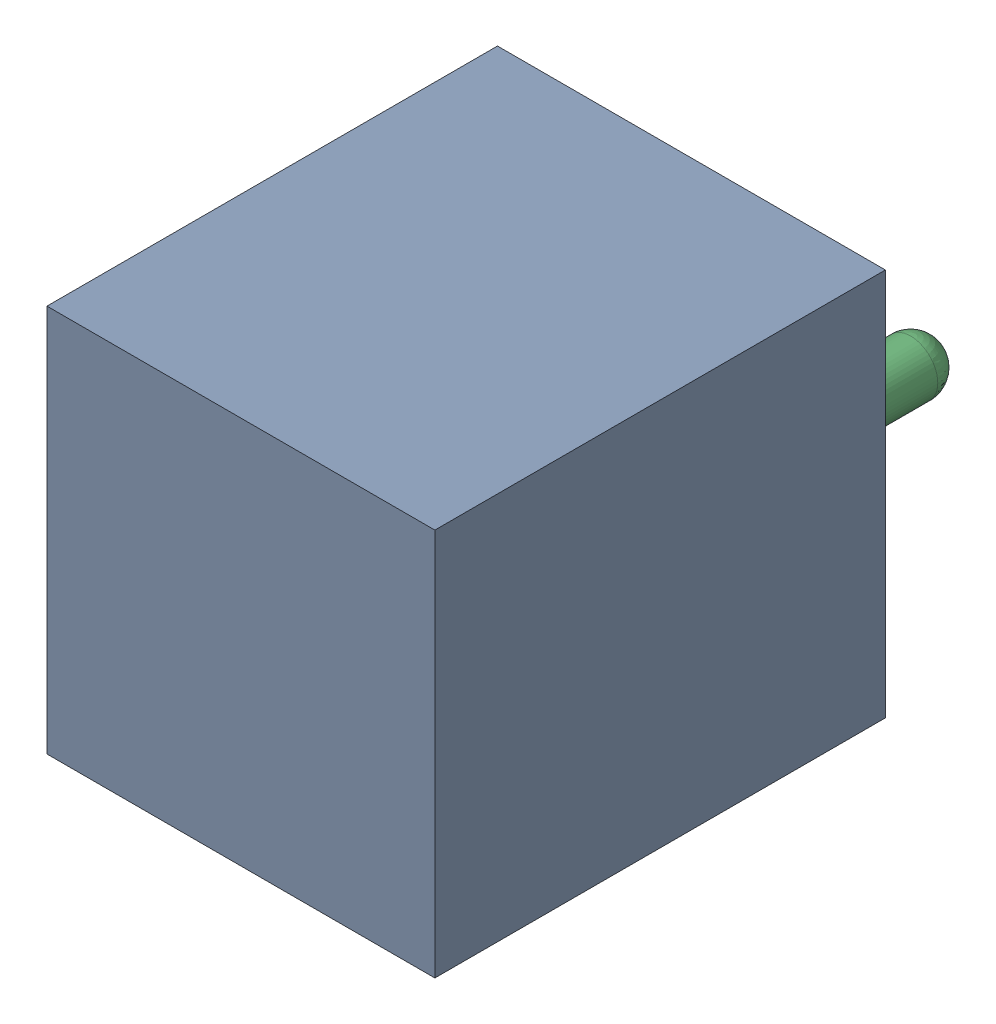
SolidWorks assembly J1, configuration Default. Lengths in mm.
Overall size (10.16 10.16 15.71).
4 component instances, 3 part files, 0 mates.
Components (placement in the parent):
- Open CASCADE STEP translator 6.8 1.5.1-1: Open CASCADE STEP translator 6.8 1.5.1 [Default] at origin size (10.16 10.16 15.71)
  - Body_1_4-1: Body_1_4 [Default] at origin size (10.16 10.16 11.8)
  - Pin_1_2-1: Pin_1_2 [Default] x (0 -1 0) z (0 0 1) size (1.42 1.42 10.52)
  - Pin_2_2-1: Pin_2_2 [Default] at (5.08 5.08 0) x (0 -1 0) z (0 0 1) size (1.42 1.42 10.52)
